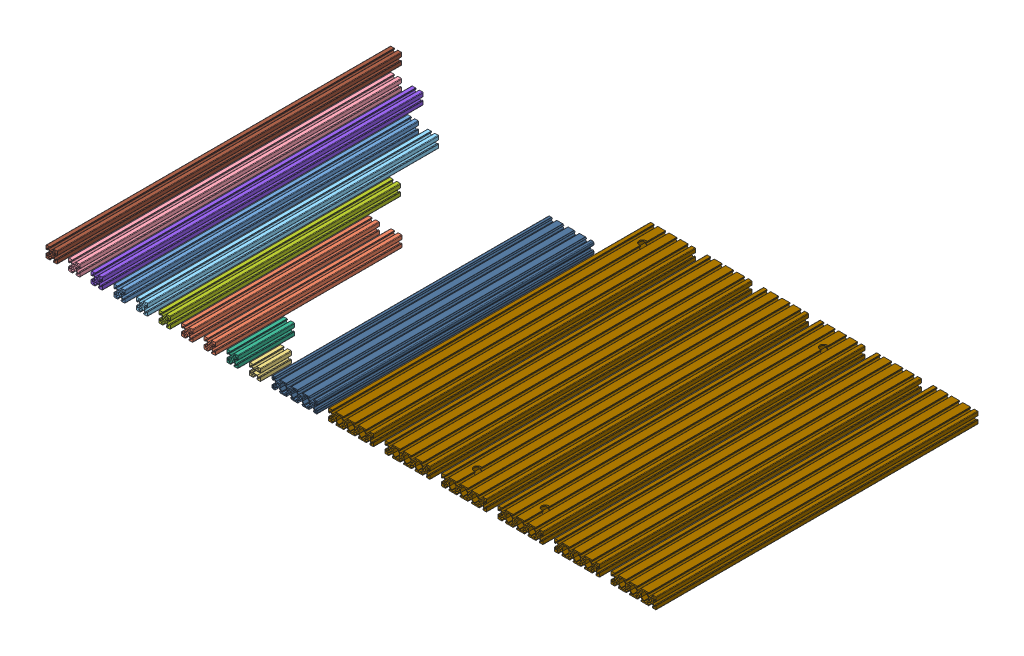
SolidWorks assembly Assem1, configuration Default. Lengths in mm.
Overall size (1080.02 20 609.5).
17 component instances, 11 part files, 49 mates.
Components (placement in the parent):
- HFS5-2020-519_5-2: HFS5-2020-519_5 [Default] at (120 0 0) size (20 20 519.5)
- HFS5-2020-330-1: HFS5-2020-330 [Cut-out Corner Post] at (280 0 0) size (20 20 330)
- HFS5-2020-54.5-1: HFS5-2020-54.5 [Default] at (360 0 0) size (20 20 54.5)
- HFS5-2020-330-2: HFS5-2020-330 [Default] at (240 0 0) size (20 20 330)
- HFS5-2020-569.5-1: HFS5-2020-569.5 [Default] at (40 0 0) size (20 20 569.5)
- HFS5-2020-515-1: HFS5-2020-515 [Default] at (160 0 0) size (20 20 515)
- HFS5-2020-100-1: HFS5-2020-100 [Default] at (320 0 0) size (20 20 100)
- HFS5-2020-407.5-1: HFS5-2020-407.5 [Default] at (200 0 0) size (20 20 407.5)
- HFS5-2020-567.5-1: HFS5-2020-567.5 [Default] at (80 0 0) size (20 20 567.5)
- HFS5-2080-569_5-1: HFS5-2080-569_5 [BackTop] at (530.015 0 0) x (0 1 0) z (0 0 1) size (20 80 569.5)
- HFS5-2080-569_5-2: HFS5-2080-569_5 [Default] at (630.015 0 0) x (0 1 0) z (0 0 1) size (20 80 569.5)
- HFS5-2080-569_5-3: HFS5-2080-569_5 [FrontTop] at (730.015 0 0) x (0 1 0) z (0 0 1) size (20 80 569.5)
- HFS5-2080-569_5-4: HFS5-2080-569_5 [LeftTop] at (830.015 0 0) x (0 1 0) z (0 0 1) size (20 80 569.5)
- HFS5-2080-569_5-5: HFS5-2080-569_5 [Top Right] at (1030.015 0 0) x (0 1 0) z (0 0 1) size (20 80 569.5)
- HFS5-2080-569_5-6: HFS5-2080-569_5 [SidesBottom] at (930.015 0 0) x (0 1 0) z (0 0 1) size (20 80 569.5)
- V-Slot_20mmX80mm489.5mm-1: V-Slot_20mmX80mm489.5mm [Default] at (399.9975 0 -244.75) x (0 1 0) z (0 0 1) size (20 80.02 489.5)
- HFS5-2020-609_5(holes_added)-1: HFS5-2020-609_5(holes_added) [Default] at origin size (20 20 609.5)
Mates (geometry in assembly coordinates):
- Coincident3: coordinate: point of HFS5-2020-609_5(holes_added)-1; point of assembly
- Coincident4: coincident aligned: plane of HFS5-2020-609_5(holes_added)-1 through (-9 9 0) normal (0 0 1); plane of HFS5-2020-519_5-2 through (125.4973 9 0) normal (0 0 1)
- Coincident5: coincident aligned: plane of HFS5-2020-609_5(holes_added)-1 through (-9 9 0) normal (0 0 1); plane of HFS5-2020-330-2 through (245.4973 9 0) normal (0 0 1)
- Coincident6: coincident aligned: plane of HFS5-2020-609_5(holes_added)-1 through (-9 9 0) normal (0 0 1); plane of HFS5-2020-569.5-1 through (31 9 0) normal (0 0 1)
- Coincident7: coincident aligned: plane of HFS5-2020-609_5(holes_added)-1 through (-9 9 0) normal (0 0 1); plane of HFS5-2020-54.5-1 through (365.4973 9 0) normal (0 0 1)
- Coincident8: coincident aligned: plane of HFS5-2020-609_5(holes_added)-1 through (-9 9 0) normal (0 0 1); plane of HFS5-2020-515-1 through (165.4973 9 0) normal (0 0 1)
- Coincident9: coincident aligned: plane of HFS5-2020-609_5(holes_added)-1 through (-9 9 0) normal (0 0 1); plane of HFS5-2020-100-1 through (325.4973 9 0) normal (0 0 1)
- Coincident10: coincident aligned: plane of HFS5-2020-609_5(holes_added)-1 through (-9 9 0) normal (0 0 1); plane of HFS5-2020-407.5-1 through (205.4973 9 0) normal (0 0 1)
- Coincident11: coincident aligned: plane of HFS5-2020-609_5(holes_added)-1 through (-9 9 0) normal (0 0 1); plane of HFS5-2020-330-1 through (285.4973 9 0) normal (0 0 1)
- Coincident12: coincident aligned: plane of HFS5-2020-609_5(holes_added)-1 through (-9 9 0) normal (0 0 1); plane of HFS5-2020-567.5-1 through (85.4973 9 0) normal (0 0 1)
- Coincident13: coincident aligned: plane of HFS5-2020-609_5(holes_added)-1 through (-9 9 0) normal (0 0 1); plane of HFS5-2080-569_5-1 through (551.2123 -9.7 0) normal (0 0 1)
- Coincident14: coincident aligned: plane of HFS5-2020-609_5(holes_added)-1 through (-9 9 0) normal (0 0 1); plane of HFS5-2080-569_5-2 through (651.2123 -9.7 0) normal (0 0 1)
- Coincident15: coincident aligned: plane of HFS5-2020-609_5(holes_added)-1 through (-9 9 0) normal (0 0 1); plane of HFS5-2080-569_5-3 through (751.2123 -9.7 0) normal (0 0 1)
- Coincident16: coincident aligned: plane of HFS5-2020-609_5(holes_added)-1 through (-9 9 0) normal (0 0 1); plane of HFS5-2080-569_5-4 through (851.2123 -9.7 0) normal (0 0 1)
- Coincident17: coincident aligned: plane of HFS5-2020-609_5(holes_added)-1 through (-9 9 0) normal (0 0 1); plane of HFS5-2080-569_5-6 through (951.2123 -9.7 0) normal (0 0 1)
- Coincident18: coincident aligned: plane of HFS5-2020-609_5(holes_added)-1 through (-9 9 0) normal (0 0 1); plane of HFS5-2080-569_5-5 through (1051.2123 -9.7 0) normal (0 0 1)
- Coincident19: coincident aligned: plane of HFS5-2020-609_5(holes_added)-1 through (-9 9 0) normal (0 0 1); plane of V-Slot_20mmX80mm489.5mm-1 through (405.2873 -4.9072 0) normal (0 0 1)
- Coincident20: coincident aligned: plane of HFS5-2020-609_5(holes_added)-1 through (9 10 -609.5) normal (0 1 0); plane of HFS5-2020-569.5-1 through (36.7 10 -569.5) normal (0 1 0)
- Coincident21: coincident aligned: plane of HFS5-2020-609_5(holes_added)-1 through (9 10 -609.5) normal (0 1 0); plane of HFS5-2020-519_5-2 through (131.1973 10 -519.5) normal (0 1 0)
- Coincident22: coincident aligned: plane of HFS5-2020-609_5(holes_added)-1 through (9 10 -609.5) normal (0 1 0); plane of HFS5-2020-515-1 through (171.1973 10 -515) normal (0 1 0)
- Coincident23: coincident aligned: plane of HFS5-2020-609_5(holes_added)-1 through (9 10 -609.5) normal (0 1 0); plane of HFS5-2020-330-2 through (251.1973 10 -330) normal (0 1 0)
- Coincident24: coincident aligned: plane of HFS5-2020-609_5(holes_added)-1 through (9 10 -609.5) normal (0 1 0); plane of HFS5-2020-330-1 through (291.1973 10 -330) normal (0 1 0)
- Coincident25: coincident aligned: plane of HFS5-2020-609_5(holes_added)-1 through (9 10 -609.5) normal (0 1 0); plane of HFS5-2020-100-1 through (331.1973 10 -100) normal (0 1 0)
- Coincident26: coincident aligned: plane of HFS5-2020-609_5(holes_added)-1 through (9 10 -609.5) normal (0 1 0); plane of HFS5-2020-54.5-1 through (371.1973 10 -54.5) normal (0 1 0)
- Coincident28: coincident aligned: plane of HFS5-2020-609_5(holes_added)-1 through (9 10 -609.5) normal (0 1 0); plane of HFS5-2020-407.5-1 through (211.1973 10 -407.5) normal (0 1 0)
- Coincident29: coincident aligned: plane of HFS5-2020-609_5(holes_added)-1 through (9 10 -609.5) normal (0 1 0); plane of HFS5-2020-567.5-1 through (91.1973 10 -567.5) normal (0 1 0)
- Coincident30: coincident aligned: plane of HFS5-2020-609_5(holes_added)-1 through (9 10 -609.5) normal (0 1 0); plane of V-Slot_20mmX80mm489.5mm-1 through (419.4061 10 -489.5) normal (0 1 0)
- Coincident31: coincident aligned: plane of HFS5-2020-609_5(holes_added)-1 through (9 10 -609.5) normal (0 1 0); plane of HFS5-2080-569_5-1 through (531.2123 10 -569.5) normal (0 1 0)
- Coincident32: coincident aligned: plane of HFS5-2020-609_5(holes_added)-1 through (9 10 -609.5) normal (0 1 0); plane of HFS5-2080-569_5-2 through (631.2123 10 -569.5) normal (0 1 0)
- Coincident33: coincident aligned: plane of HFS5-2020-609_5(holes_added)-1 through (9 10 -609.5) normal (0 1 0); plane of HFS5-2080-569_5-3 through (731.2123 10 -569.5) normal (0 1 0)
- Coincident34: coincident aligned: plane of HFS5-2020-609_5(holes_added)-1 through (9 10 -609.5) normal (0 1 0); plane of HFS5-2080-569_5-4 through (831.2123 10 -569.5) normal (0 1 0)
- Coincident35: coincident aligned: plane of HFS5-2020-609_5(holes_added)-1 through (9 10 -609.5) normal (0 1 0); plane of HFS5-2080-569_5-6 through (931.2123 10 -569.5) normal (0 1 0)
- Coincident36: coincident aligned: plane of HFS5-2020-609_5(holes_added)-1 through (9 10 -609.5) normal (0 1 0); plane of HFS5-2080-569_5-5 through (1051.2123 10 -569.5) normal (0 1 0)
- Distance1: distance = 20 mm anti-aligned: plane of HFS5-2020-609_5(holes_added)-1 through (10 3.3 -609.5) normal (1 0 0); plane of HFS5-2020-569.5-1 through (30 9 -569.5) normal (-1 0 0)
- Distance3: distance = 20 mm anti-aligned: plane of HFS5-2020-519_5-2 through (130 3.3 -519.5) normal (1 0 0); plane of HFS5-2020-515-1 through (150 9 -515) normal (-1 0 0)
- Distance6: distance = 20 mm anti-aligned: plane of HFS5-2020-330-1 through (290 3.3 -330) normal (1 0 0); plane of HFS5-2020-100-1 through (310 9 -100) normal (-1 0 0)
- Distance7: distance = 20 mm anti-aligned: plane of HFS5-2020-100-1 through (330 3.3 -100) normal (1 0 0); plane of HFS5-2020-54.5-1 through (350 9 -54.5) normal (-1 0 0)
- Distance12: distance = 20 mm anti-aligned: plane of V-Slot_20mmX80mm489.5mm-1 through (470.015 4.9072 -489.5) normal (1 0 0); plane of HFS5-2080-569_5-1 through (490.015 9 -569.5) normal (-1 0 0)
- Distance13: distance = 20 mm anti-aligned: plane of HFS5-2080-569_5-1 through (570.015 3.3 -569.5) normal (1 0 0); plane of HFS5-2080-569_5-2 through (590.015 9 -569.5) normal (-1 0 0)
- Distance14: distance = 20 mm anti-aligned: plane of HFS5-2080-569_5-2 through (670.015 3.3 -569.5) normal (1 0 0); plane of HFS5-2080-569_5-3 through (690.015 9 -569.5) normal (-1 0 0)
- Distance15: distance = 20 mm anti-aligned: plane of HFS5-2080-569_5-3 through (770.015 3.3 -569.5) normal (1 0 0); plane of HFS5-2080-569_5-4 through (790.015 9 -569.5) normal (-1 0 0)
- Distance16: distance = 20 mm anti-aligned: plane of HFS5-2080-569_5-4 through (870.015 3.3 -569.5) normal (1 0 0); plane of HFS5-2080-569_5-6 through (890.015 9 -569.5) normal (-1 0 0)
- Distance17: distance = 20 mm anti-aligned: plane of HFS5-2080-569_5-6 through (970.015 3.3 -569.5) normal (1 0 0); plane of HFS5-2080-569_5-5 through (990.015 9 -569.5) normal (-1 0 0)
- Distance18: distance = 20 mm anti-aligned: plane of HFS5-2020-515-1 through (170 3.3 -515) normal (1 0 0); plane of HFS5-2020-407.5-1 through (190 9 -407.5) normal (-1 0 0)
- Distance21: distance = 20 mm anti-aligned: plane of HFS5-2020-330-1 through (270 9 -330) normal (-1 0 0); plane of HFS5-2020-330-2 through (250 3.3 -330) normal (1 0 0)
- Distance22: distance = 20 mm anti-aligned: plane of HFS5-2020-54.5-1 through (370 3.3 -54.5) normal (1 0 0); plane of V-Slot_20mmX80mm489.5mm-1 through (390 4.9072 -489.5) normal (-1 0 0)
- Distance23: distance = 20 mm anti-aligned: plane of HFS5-2020-330-2 through (230 9 -330) normal (-1 0 0); plane of HFS5-2020-407.5-1 through (210 3.3 -407.5) normal (1 0 0)
- Distance24: distance = 20 mm anti-aligned: plane of HFS5-2020-567.5-1 through (90 3.3 -567.5) normal (1 0 0); plane of HFS5-2020-519_5-2 through (110 9 -519.5) normal (-1 0 0)
- Distance25: distance = 20 mm anti-aligned: plane of HFS5-2020-567.5-1 through (70 9 -567.5) normal (-1 0 0); plane of HFS5-2020-569.5-1 through (50 3.3 -569.5) normal (1 0 0)
